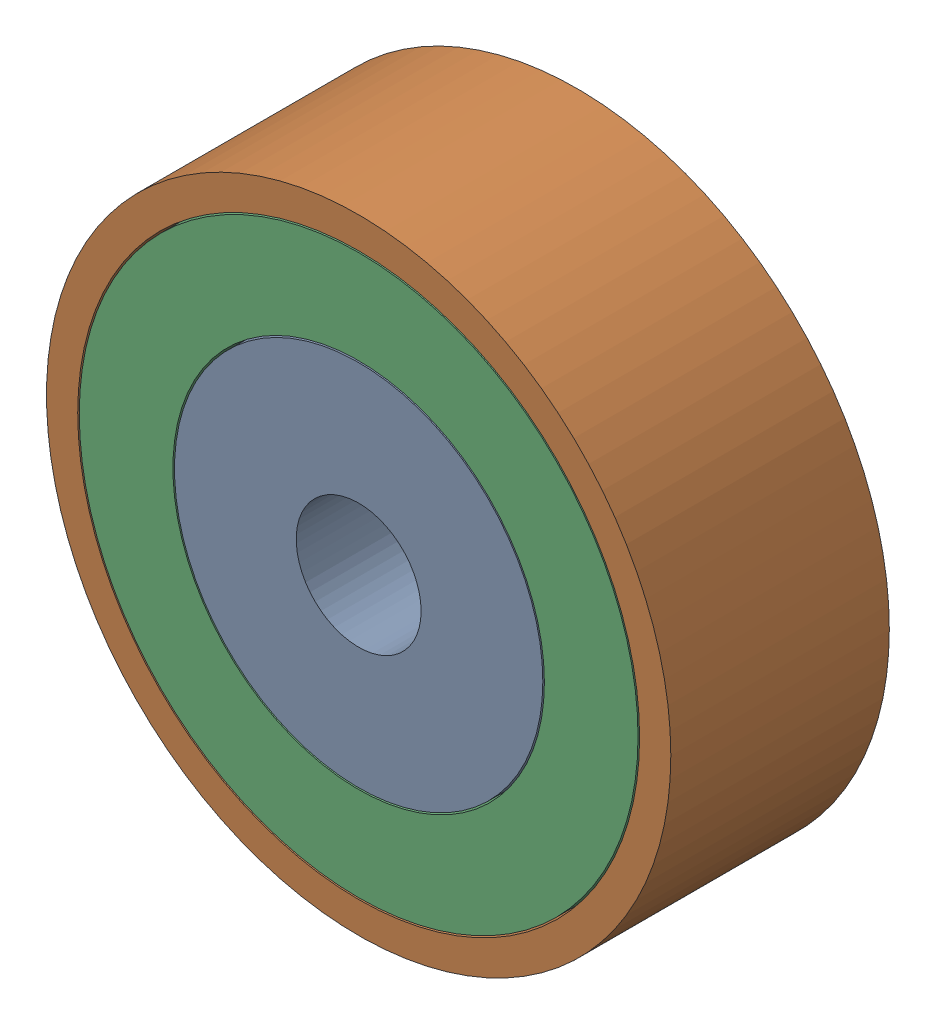
SolidWorks assembly 镜向轴承5, configuration 默认. Lengths in mm.
Overall size (20 20 7).
3 component instances, 3 part files, 4 mates.
Components (placement in the parent):
- 镜向轴承内圈-1: 镜向轴承内圈 [默认] at (-5.0655 0.8032 -6.5) size (11.8 11.8 7)
- 镜向轴承外圈-1: 镜向轴承外圈 [默认] at (-5.0655 0.8032 -6.5) size (20 20 7)
- 镜向轴承中圈-1: 镜向轴承中圈 [默认] at (-5.0655 0.8032 -6.5) size (17.9 17.9 7)
Mates (geometry in assembly coordinates):
- 重合1: coincident: plane of ? through (-5.0655 0.8032 -13.5) normal (0 0 -1); plane of ? through (-5.0655 0.8032 -13.5) normal (0 0 -1)
- 重合2: coincident: plane of ? through (-5.0655 0.8032 -13.5) normal (0 0 -1); plane of ? through (-5.0655 0.8032 -13.5) normal (0 0 -1)
- 同心1: concentric: cylinder of ? through (-5.0655 0.8032 -13.5) axis (0 0 1) radius 9; cylinder of ? through (-5.0655 0.8032 -13.5) axis (0 0 1) radius 8.95
- 同心2: concentric: cylinder of ? through (-5.0655 0.8032 -13.5) axis (0 0 1) radius 5.9; cylinder of ? through (-5.0655 0.8032 -13.5) axis (0 0 1) radius 5.95
